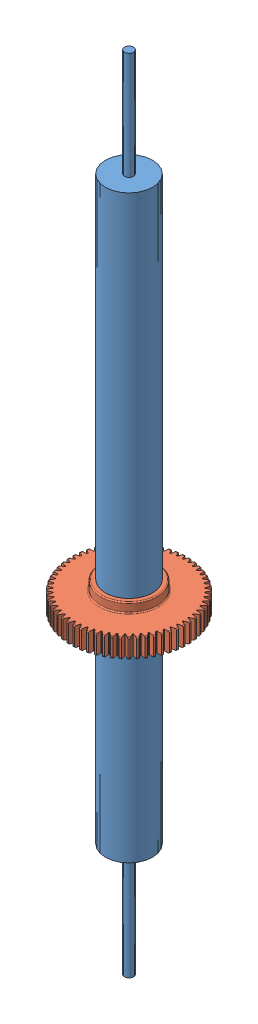
SolidWorks assembly matedshaftGear, configuration Default. Lengths in mm.
Overall size (196.76 849.6 124.08).
3 component instances, 3 part files, 3 mates.
Components (placement in the parent):
- newShaft-1: newShaft [Default] at (221.2792 34.9694 556.8123) size (50 849.6 50)
- outputGeartoSprocketGear-1: outputGeartoSprocketGear [2664N26] at (221.2792 347.9694 556.8123) x (1 0 0) z (0 1 0) size (124.08 124.08 30.08)
- 91390A109_ALLOY STEEL CUP POINT SET SCREW-1: 91390A109_ALLOY STEEL CUP POINT SET SCREW [91390A109] at (203.5323 372.9194 553.2416) x (0 0 1) z (-1 0 0) size (3.11 3.46 25.5)
Mates (geometry in assembly coordinates):
- Concentric1: concentric: cylinder of newShaft-1 through (221.2792 824.5694 556.8123) axis (0 -1 0) radius 25; cylinder of outputGeartoSprocketGear-1 through (221.2792 347.8855 556.8123) axis (0 1 0) radius 25
- Concentric3: concentric: cylinder of outputGeartoSprocketGear-1 through (159.2414 372.9194 553.2416) axis (1 0 0) radius 1.5; line of assembly
- Tangent3: tangent: cylinder of outputGeartoSprocketGear-1 through (221.2792 367.9694 556.8123) axis (0 -1 0) radius 30; plane of 91390A109_ALLOY STEEL CUP POINT SET SCREW-1 through (191.2792 372.9194 553.2416) normal (-1 0 0)
